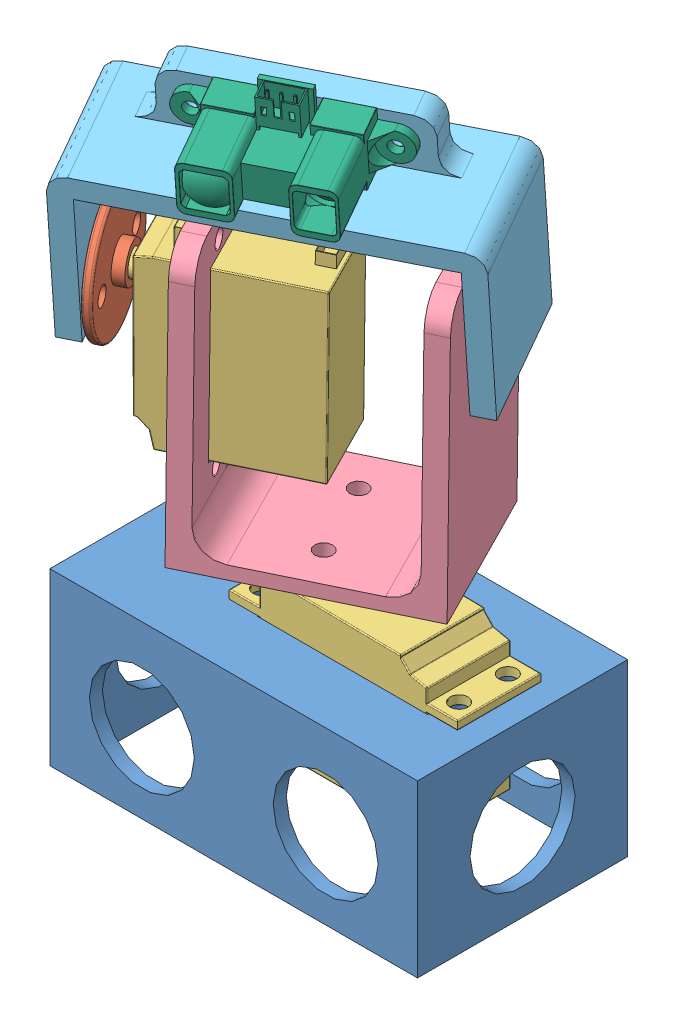
SolidWorks assembly FullAssembly, configuration Default. Lengths in mm.
Overall size (97.43 157.92 82.33).
10 component instances, 6 part files, 15 mates.
Components (placement in the parent):
- Base-2: Base [Default] at (-213.4648 -103.151 221.6295) size (88.9 41.27 50.8)
- ServoWithstickattach-1: ServoWithstickattach [Default] at (-150.1162 -58.1847 245.6604) x (0.729776 -0.009675 0.683618) z (0.013256 0.999912 0) size (54.52 53.16 43.26) (flexible)
  - servoAttachment-1: servoAttachment [Default] at (-47.3139 23.4111 8.566) x (-0.938757 0.344579 0) z (0 0 1) size (30 30 4.5)
  - servo motor-1: servo motor [Default] at (-17.707 37.309 -3.5248) x (-0.729776 -0.683558 -0.013256) z (-0.683618 0.72984 0) size (55.24 41.08 20.19)
- TopRotator-1: TopRotator [Default] at (-154.3463 -45.0615 167.7939) x (-0.89316 0.011841 0.449582) z (-0.449543 0.00596 -0.893239) size (50.8 66.67 38.1)
- ServoWithstickattach-2: ServoWithstickattach [Default] at (-167.2743 -34.1921 139.7359) x (-0.41919 -0.212071 -0.882783) z (0.905379 -0.025261 -0.423852) size (38.61 59.09 44.63) (flexible)
  - servoAttachment-1: servoAttachment [Default] at (-58.5868 24.7182 -63.2816) x (-0.938211 -0.344598 0.031818) z (-0.022104 -0.032085 -0.999241) size (30 30 4.5)
  - servo motor-1: servo motor [Default] at (-41.6889 -3.0515 -50.6637) x (-0.21761 0.975946 -0.013256) z (-0.975716 -0.217171 0.028557) size (55.24 41.08 20.19)
- TiltRotator-1: TiltRotator [Default] at (-212.8561 0.0914 201.0596) x (-0.893258 -0.001415 0.449543) z (-0.445387 0.138483 -0.884564) size (79.5 50.8 30.48)
- ProxSensor-1: ProxSensor [Default] at (-173.2881 42.4532 202.126) x (-0.893258 -0.001415 0.449543) z (0.445387 -0.138483 0.884564) size (44.5 18.9 21.6)
Mates (geometry in assembly coordinates):
- Concentric1: concentric aligned: cylinder of Base-2 through (-134.0263 -103.152 190.324) axis (0 1 0) radius 2.159; cylinder of ServoWithstickattach-1/servo motor-1 through (-134.0263 -69.7427 190.324) axis (0 1 0) radius 2.159
- Concentric2: concentric aligned: cylinder of Base-2 through (-134.0263 -103.152 202.135) axis (0 1 0) radius 2.159; cylinder of ServoWithstickattach-1/servo motor-1 through (-134.0263 -69.7427 202.135) axis (0 1 0) radius 2.159
- Coincident5: coincident anti-aligned: plane of Base-2 through (-213.4648 -61.876 221.6295) normal (0 1 0); plane of ServoWithstickattach-1/servo motor-1 through (-157.775 -61.876 186.133) normal (0 -1 0)
- Concentric4: concentric aligned: cylinder of TopRotator-1 through (-142.9425 -31.305 190.0846) axis (-0.89316 0.011841 0.449582) radius 2.159; cylinder of ServoWithstickattach-2/servo motor-1 through (-181.2896 -30.7966 209.3871) axis (-0.89316 0.011841 0.449582) radius 2.159
- Concentric5: concentric aligned: cylinder of TopRotator-1 through (-148.252 -31.2346 179.5346) axis (-0.89316 0.011841 0.449582) radius 2.159; cylinder of ServoWithstickattach-2/servo motor-1 through (-186.5992 -30.7262 198.8371) axis (-0.89316 0.011841 0.449582) radius 2.159
- Coincident7: coincident anti-aligned: plane of TopRotator-1 through (-199.6767 -41.2852 190.6327) normal (-0.89316 0.011841 0.449582); plane of ServoWithstickattach-2/servo motor-1 through (-186.1171 -6.9818 216.6674) normal (0.89316 -0.011841 -0.449582)
- Coincident14: coincident anti-aligned: plane of TiltRotator-1 through (-150.215 48.7285 191.4909) normal (0.445387 -0.138483 0.884564); plane of ProxSensor-1 through (-156.7628 42.4794 193.8094) normal (-0.445387 0.138483 -0.884564)
- Concentric7: concentric anti-aligned: cylinder of TiltRotator-1 through (-162.4197 44.2383 182.5746) axis (0.445387 -0.138483 0.884564) radius 1.6; cylinder of ProxSensor-1 through (-147.1425 39.4882 212.916) axis (-0.445387 0.138483 -0.884564) radius 1.6
- Concentric8: concentric anti-aligned: cylinder of TiltRotator-1 through (-195.4702 44.1859 199.2077) axis (0.445387 -0.138483 0.884564) radius 1.6; cylinder of ProxSensor-1 through (-180.193 39.4358 229.5491) axis (-0.445387 0.138483 -0.884564) radius 1.6
- Concentric11: concentric aligned: cylinder of ServoWithstickattach-1/servoAttachment-1 through (-172.8103 -49.3171 187.7214) axis (0.013256 0.999912 0) radius 2.159; cylinder of TopRotator-1 through (-172.7507 -44.8185 187.7214) axis (0.013256 0.999912 0) radius 2.159
- Concentric12: concentric aligned: cylinder of ServoWithstickattach-1/servoAttachment-1 through (-164.2465 -49.4306 204.7376) axis (0.013256 0.999912 0) radius 2.159; cylinder of TopRotator-1 through (-164.1869 -44.932 204.7376) axis (0.013256 0.999912 0) radius 2.159
- Coincident15: coincident anti-aligned: plane of ServoWithstickattach-1/servoAttachment-1 through (-168.4688 -44.8743 196.2295) normal (0.013256 0.999912 0); plane of TopRotator-1 through (-154.3463 -45.0615 167.7939) normal (-0.013256 -0.999912 0)
- Concentric14: concentric anti-aligned: cylinder of ServoWithstickattach-2/servoAttachment-1 through (-205.922 5.298 204.8441) axis (-0.893258 -0.001415 0.449543) radius 2.159; cylinder of TiltRotator-1 through (-214.2525 5.2848 209.0365) axis (0.893258 0.001415 -0.449543) radius 2.159
- Concentric15: concentric anti-aligned: cylinder of ServoWithstickattach-2/servoAttachment-1 through (-197.4374 2.6599 221.695) axis (-0.893258 -0.001415 0.449543) radius 2.159; cylinder of TiltRotator-1 through (-205.7679 2.6467 225.8875) axis (0.893258 0.001415 -0.449543) radius 2.159
- Coincident18: coincident anti-aligned: plane of ServoWithstickattach-2/servoAttachment-1 through (-205.6994 3.9726 215.2925) normal (-0.893258 -0.001415 0.449543); plane of TiltRotator-1 through (-212.8561 0.0914 201.0596) normal (0.893258 0.001415 -0.449543)
